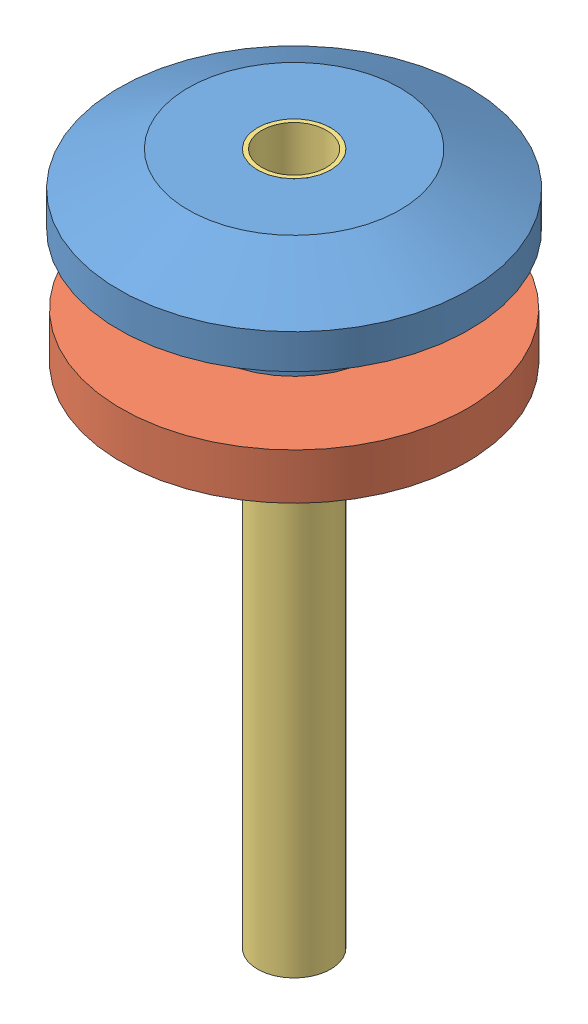
SolidWorks assembly ineterface exterieur, configuration Défaut. Lengths in mm.
Overall size (15.18 30 15.18).
3 component instances, 3 part files, 4 mates.
Components (placement in the parent):
- jonction exterxieure-1: jonction exterxieure [Défaut] at (-1.6616 5.6324 27.0418) size (15.18 10 15.18)
- rondelle bloquante-1: rondelle bloquante [Défaut] at (-1.6616 -1.2384 27.0418) x (1 0 0) z (0 -1 0) size (15 15 2)
- tube flex 1_8-1: tube flex 1_8 [Défaut] at (-1.6616 4.7616 27.0418) x (0 -1 0) z (0.807237 0 0.590227) size (30 3.17 3.17)
Mates (geometry in assembly coordinates):
- Coaxiale1: concentric: cylinder of jonction exterxieure-1 through (-1.6616 5.6324 27.0418) axis (0 -1 0) radius 1.59; cylinder of tube flex 1_8-1 through (-1.6616 -24.5474 27.0418) axis (0 1 0) radius 1.5875
- Coaxiale2: concentric anti-aligned: cylinder of jonction exterxieure-1 through (-1.6616 5.6324 27.0418) axis (0 -1 0) radius 3.59; cylinder of rondelle bloquante-1 through (-1.6616 -3.2384 27.0418) axis (0 1 0) radius 3.59
- Coïncidente1: coincident anti-aligned: plane of jonction exterxieure-1 through (1.9284 -3.2384 27.0418) normal (0 1 0); plane of rondelle bloquante-1 through (-1.6616 -3.2384 27.0418) normal (0 -1 0)
- Coïncidente2: coincident aligned: plane of jonction exterxieure-1 through (-0.0716 4.7616 27.0418) normal (0 1 0); plane of tube flex 1_8-1 through (-1.6616 5.4526 27.0418) normal (0 1 0)
